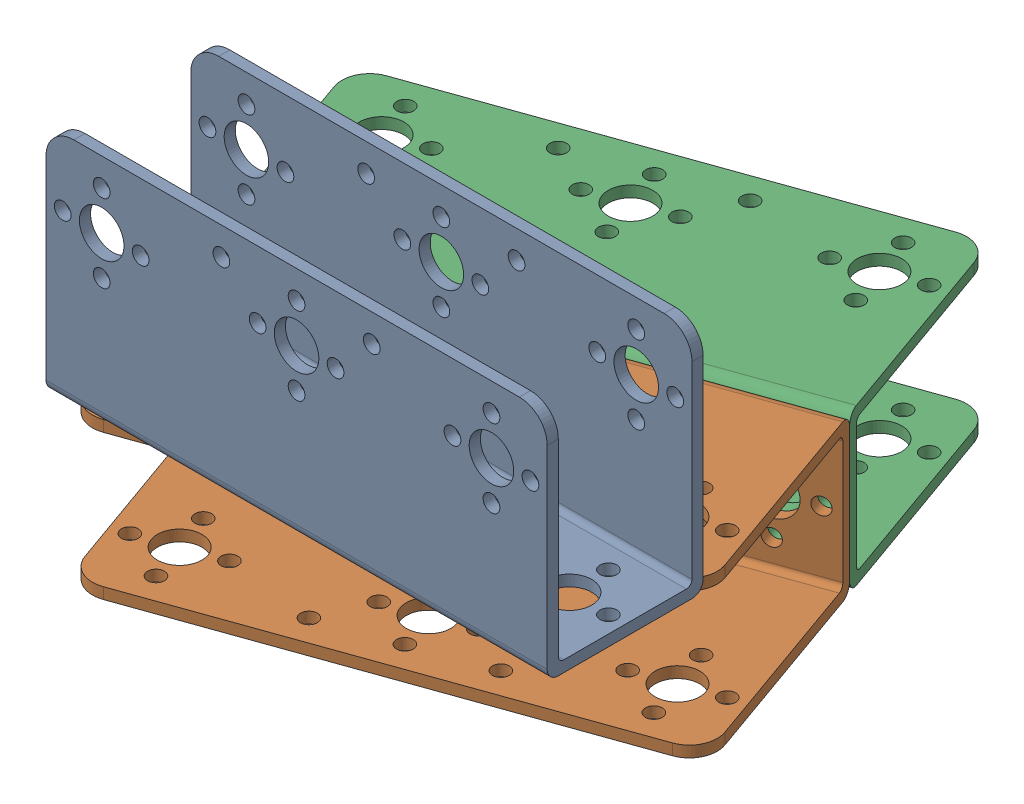
SolidWorks assembly Prova Assieme, configuration Default. Lengths in mm.
Overall size (113.45 69.86 109.03).
3 component instances, 1 part files, 3 mates.
Components (placement in the parent):
- Parte Telaio 1-4: Parte Telaio 1 [Default] at (-50.9317 -15.9949 14) size (90 41.86 28)
- Parte Telaio 1-5: Parte Telaio 1 [Default] at (-60.356 -43.9949 -24.7859) x (0.942233 0 -0.334958) z (0 -1 0) size (90 41.86 28)
- Parte Telaio 1-6: Parte Telaio 1 [Default] at (-60.356 -15.9949 -24.7859) x (0.942233 0 -0.334958) z (0 1 0) size (90 41.86 28)
Mates (geometry in assembly coordinates):
- Coincident1: coincident anti-aligned: circle of Parte Telaio 1-5; circle of Parte Telaio 1-6
- Coincident2: coincident anti-aligned: circle of Parte Telaio 1-5; circle of Parte Telaio 1-6
- Coincident3: coincident anti-aligned: circle of Parte Telaio 1-4; circle of Parte Telaio 1-5
